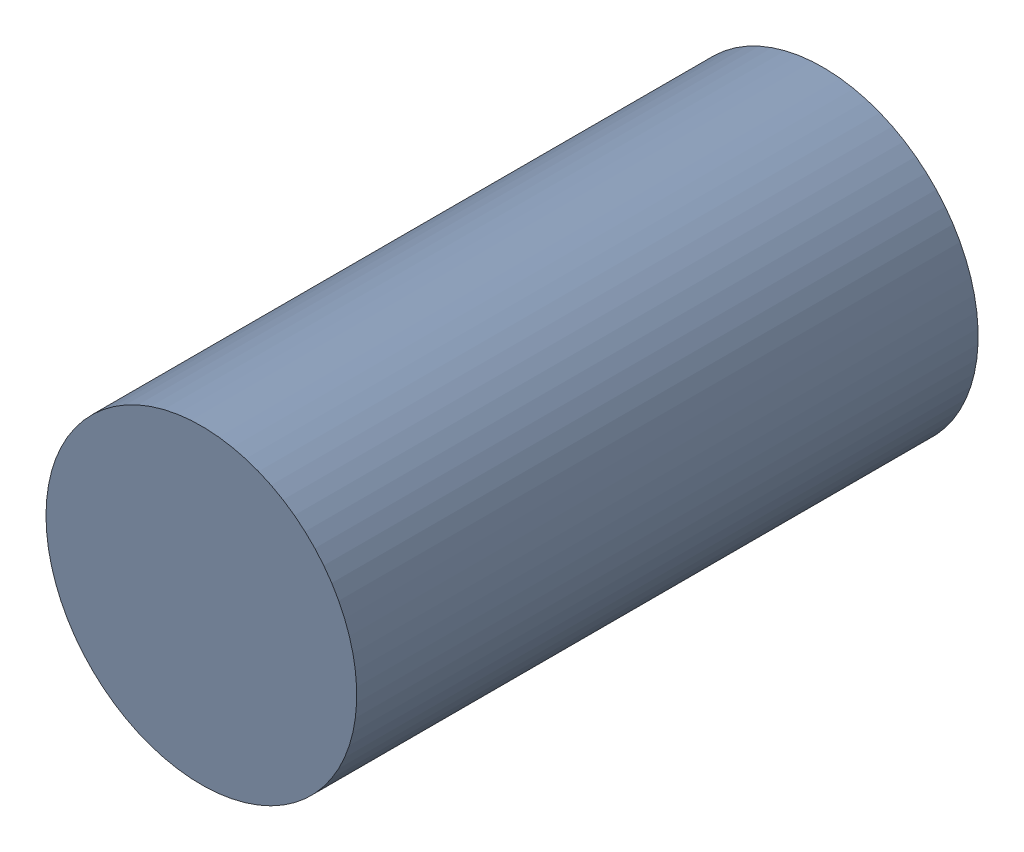
SolidWorks assembly MH8_2.step, configuration Default. Lengths in mm.
Overall size (1 1 2).
2 component instances, 1 part files, 0 mates.
Components (placement in the parent):
- 11929539264.step-1: 11929539264.step [Default] at (142.3363 50.9276 -1.5) x (-1 0 0) z (0 0 1) size (1 1 2)
  - Cylinder_2.step-7: Cylinder_2.step [Default] at origin size (1 1 2)
